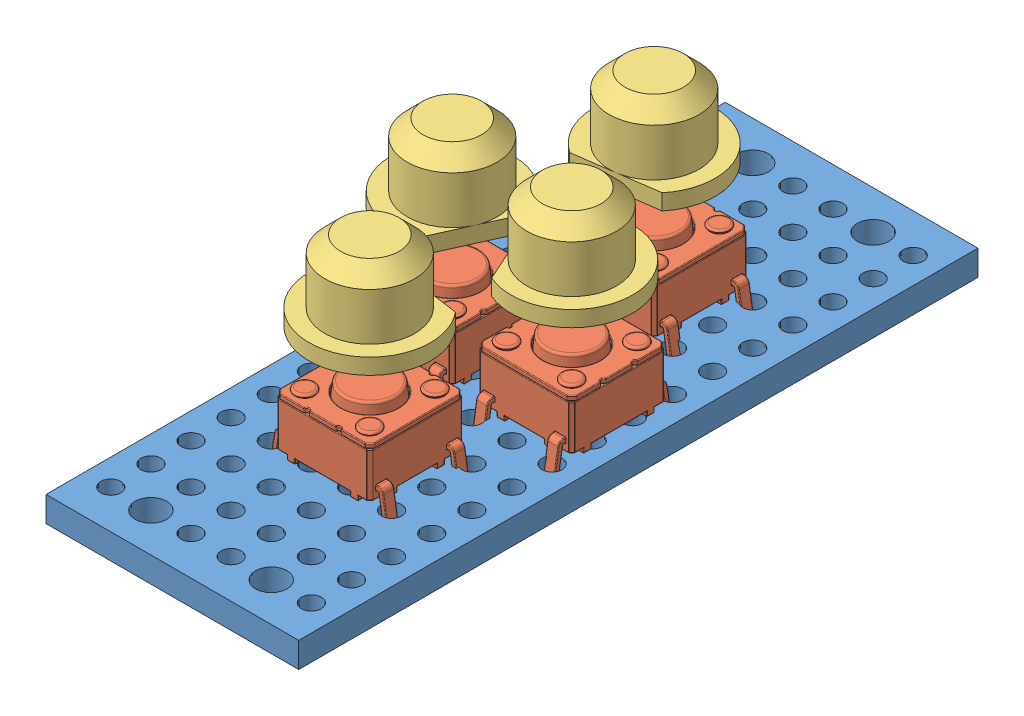
SolidWorks assembly Button Assembly, configuration Default. Lengths in mm.
Overall size (17.75 15.5 43).
9 component instances, 3 part files, 10 mates.
Components (placement in the parent):
- PCB Backplane-1: PCB Backplane [Default] at (9.1588 12.7111 25.5607) size (16 1.6 43)
- Push Tactile Button SPST-NO 6x6mm L=5mm Omron B3F-1020-1: Push Tactile Button SPST-NO 6x6mm L=5mm Omron B3F-1020 [Default] at (3.1261 14.3111 28.8114) x (0 0 1) z (0 1 0) size (7.7 6.02 7.5)
- Button Face-1: Button Face [Default] at (5.3762 21.3111 25.5607) x (0.410395 0 -0.911908) z (0.911908 0 0.410395) size (7.7 5 6.7)
- Push Tactile Button SPST-NO 6x6mm L=5mm Omron B3F-1020-2: Push Tactile Button SPST-NO 6x6mm L=5mm Omron B3F-1020 [Default] at (12.4095 14.3111 18.8083) x (1 0 0) z (0 1 0) size (7.7 6.02 7.5)
- Button Face-2: Button Face [Default] at (9.1588 21.3111 16.5581) x (0.990205 0 -0.13962) z (0.13962 0 0.990205) size (7.7 5 6.7)
- Push Tactile Button SPST-NO 6x6mm L=5mm Omron B3F-1020-3: Push Tactile Button SPST-NO 6x6mm L=5mm Omron B3F-1020 [Default] at (15.1915 14.3111 22.31) x (0 0 -1) z (0 1 0) size (7.7 6.02 7.5)
- Button Face-3: Button Face [Default] at (12.9413 21.3111 25.5607) x (0.410395 0 0.911908) z (-0.911908 0 0.410395) size (7.7 5 6.7)
- Button Face-4: Button Face [Default] at (9.1588 21.3111 34.5632) x (-0.990205 0 -0.13962) z (0.13962 0 -0.990205) size (7.7 5 6.7)
- Push Tactile Button SPST-NO 6x6mm L=5mm Omron B3F-1020-4: Push Tactile Button SPST-NO 6x6mm L=5mm Omron B3F-1020 [Default] at (12.4095 14.3111 36.8134) x (1 0 0) z (0 1 0) size (7.7 6.02 7.5)
Mates (geometry in assembly coordinates):
- Coincident1: coincident anti-aligned: plane of PCB Backplane-1 through (9.1588 14.3111 25.5607) normal (0 1 0); plane of Push Tactile Button SPST-NO 6x6mm L=5mm Omron B3F-1020-1 through (5.3762 14.3111 25.5607) normal (0 -1 0)
- Parallel1: parallel aligned: plane of PCB Backplane-1 through (1.1588 14.3111 47.0607) normal (-1 0 0); plane of Push Tactile Button SPST-NO 6x6mm L=5mm Omron B3F-1020-1 through (2.3762 14.3111 22.5607) normal (-1 0 0)
- Coincident3: coincident anti-aligned: plane of PCB Backplane-1 through (9.1588 14.3111 25.5607) normal (0 1 0); plane of Push Tactile Button SPST-NO 6x6mm L=5mm Omron B3F-1020-2 through (9.1588 14.3111 16.5581) normal (0 -1 0)
- Parallel2: parallel aligned: plane of PCB Backplane-1 through (1.1588 14.3111 4.0607) normal (0 0 -1); plane of Push Tactile Button SPST-NO 6x6mm L=5mm Omron B3F-1020-2 through (12.1588 14.3111 13.5581) normal (0 0 -1)
- Concentric1: concentric anti-aligned: cylinder of Push Tactile Button SPST-NO 6x6mm L=5mm Omron B3F-1020-1 through (5.3762 17.7111 25.5607) axis (0 -1 0) radius 1.8; cylinder of Button Face-1 through (5.3762 23.8111 25.5607) axis (0 1 0) radius 2.85
- Concentric2: concentric anti-aligned: cylinder of Push Tactile Button SPST-NO 6x6mm L=5mm Omron B3F-1020-2 through (9.1588 17.7111 16.5581) axis (0 -1 0) radius 1.8; cylinder of Button Face-2 through (9.1588 23.8111 16.5581) axis (0 1 0) radius 2.85
- Coincident5: coincident aligned: plane of Button Face-1 through (6.197 20.3111 23.7369) normal (0 -1 0); plane of Button Face-2 through (11.1392 20.3111 16.2789) normal (0 -1 0)
- Symmetric1: symmetric aligned: plane of PCB Backplane-1 through (9.1588 12.7111 25.5607) normal (0 0 1); plane of Push Tactile Button SPST-NO 6x6mm L=5mm Omron B3F-1020-1 through (8.3762 14.3111 22.5607) normal (0 0 -1); plane of Push Tactile Button SPST-NO 6x6mm L=5mm Omron B3F-1020-1 through (2.3762 14.3111 28.5607) normal (0 0 1)
- Symmetric2: symmetric aligned: plane of PCB Backplane-1 through (9.1588 12.7111 25.5607) normal (1 0 0); plane of Push Tactile Button SPST-NO 6x6mm L=5mm Omron B3F-1020-2 through (6.1588 14.3111 13.5581) normal (-1 0 0); plane of Push Tactile Button SPST-NO 6x6mm L=5mm Omron B3F-1020-2 through (12.1588 14.3111 19.5581) normal (1 0 0)
- Distance1: distance = 8 mm aligned: plane of Button Face-2 through (12.9711 22.3111 16.0206) normal (0 1 0); plane of PCB Backplane-1 through (9.1588 14.3111 25.5607) normal (0 1 0)
